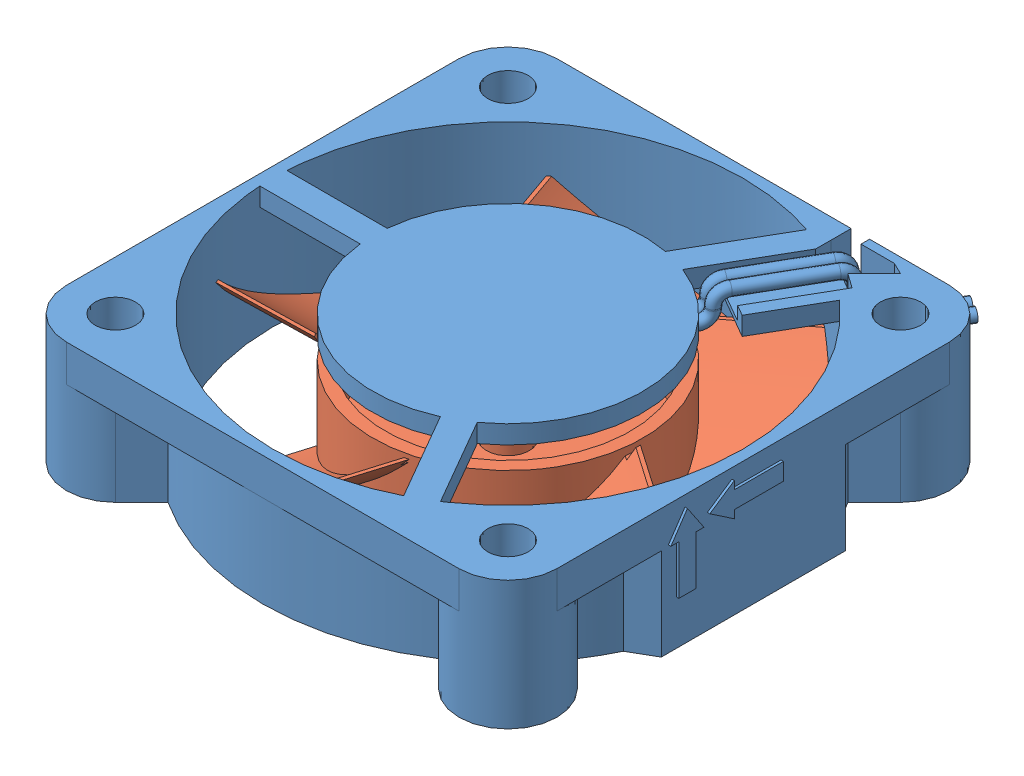
SolidWorks assembly 40x40x10 fan cooler 5v sunon, configuration Default. Lengths in mm.
Overall size (51.62 11.06 51.62).
2 component instances, 2 part files, 0 mates.
Components (placement in the parent):
- 40x40x10-1: 40x40x10 [Default] at (20 0 -20) x (0 0 -1) z (-1 0 0) size (44.65 10.7 40.2)
- blade-1: blade [Default] at (20 -3.3 -20) x (-0.569127 0 0.822249) z (0.822249 0 0.569127) size (37.1 8.47 37.1)
